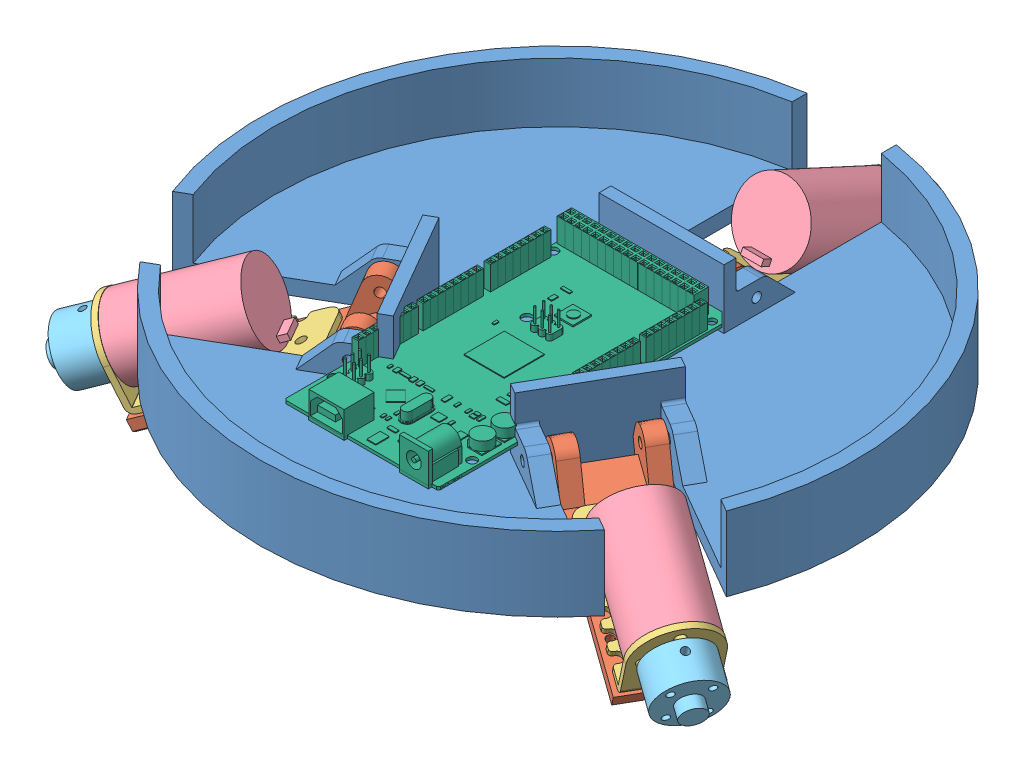
SolidWorks assembly Bottom Assembly, configuration Standard. Lengths in mm.
Overall size (238.41 65.37 229.54).
17 component instances, 6 part files, 6 mates.
Components (placement in the parent):
- Bottom Plate-1: Bottom Plate [Standard] at origin size (200 25 198.87)
- Motor Assembly-1: Motor Assembly [Standard] at (0 -10.7446 -69.3348) x (0 0.419105 0.907938) z (-1 0 0) size (87 31 28)
  - Motor Mount-1: Motor Mount [Standard] at origin size (70 14 28)
  - Motor Mount Plate-1: Motor Mount Plate [Standard] at (-33 4 12.5) size (52 27 25)
  - Motor-1: Motor [Standard] at (5.8 18.5 0) x (0 0 1) z (-1 0 0) size (24.8 24.8 53.8)
  - WheelHub-1: WheelHub [Standard] at (-36 18.5 0) x (0 0 -1) z (0 1 0) size (20 16 20)
- Motor Assembly-3: Motor Assembly [Standard] at (-59.8661 -10.9768 34.5637) x (0.782651 0.428109 -0.451864) z (0.5 0 0.866025) size (87 31 28)
  - Motor Mount-1: Motor Mount [Standard] at origin size (70 14 28)
  - Motor Mount Plate-1: Motor Mount Plate [Standard] at (-33 4 12.5) size (52 27 25)
  - Motor-1: Motor [Standard] at (5.8 18.5 0) x (0 0 1) z (-1 0 0) size (24.8 24.8 53.8)
  - WheelHub-1: WheelHub [Standard] at (-36 18.5 0) x (0 0 -1) z (0 1 0) size (20 16 20)
- Motor Assembly-5: Motor Assembly [Standard] at (60.2924 -10.4178 34.8099) x (-0.791246 0.406497 -0.456826) z (0.5 0 -0.866025) size (87 31 28)
  - Motor Mount-1: Motor Mount [Standard] at origin size (70 14 28)
  - Motor Mount Plate-1: Motor Mount Plate [Standard] at (-33 4 12.5) size (52 27 25)
  - Motor-1: Motor [Standard] at (5.8 18.5 0) x (0 0 1) z (-1 0 0) size (24.8 24.8 53.8)
  - WheelHub-1: WheelHub [Standard] at (-36 18.5 0) x (0 0 -1) z (0 1 0) size (20 16 20)
- ArduinoMega2560-1: ArduinoMega2560 [Predeterminado] at (-0.0669 11.4726 16.6208) x (0 0 1) z (-1 0 0) size (100 11.65 51.63)
Mates (geometry in assembly coordinates):
- Konzentrisch1: concentric anti-aligned: circle of Motor Assembly-1/Motor Mount-1; circle of Bottom Plate-1
- Abstand1: distance = 1 mm anti-aligned: plane of Motor Assembly-1/Motor Mount-1 through (-14 7.5558 -39.2334) normal (-1 0 0); plane of Bottom Plate-1 through (-15 5 0) normal (1 0 0)
- Konzentrisch3: concentric anti-aligned: circle of Bottom Plate-1; circle of Motor Assembly-3/Motor Mount-1
- Abstand2: distance = 1 mm anti-aligned: plane of Motor Assembly-3/Motor Mount-1 through (-26.9564 7.6219 31.7291) normal (0.5 0 0.866025); plane of Bottom Plate-1 through (7.5 5 12.9904) normal (-0.5 0 -0.866025)
- Konzentrisch4: concentric anti-aligned: circle of Motor Assembly-5/Motor Mount-1; circle of Bottom Plate-1
- Abstand3: distance = 1 mm anti-aligned: plane of Motor Assembly-5/Motor Mount-1 through (41.007 7.4642 7.5096) normal (0.5 0 -0.866025); plane of Bottom Plate-1 through (7.5 5 -12.9904) normal (-0.5 0 0.866025)
